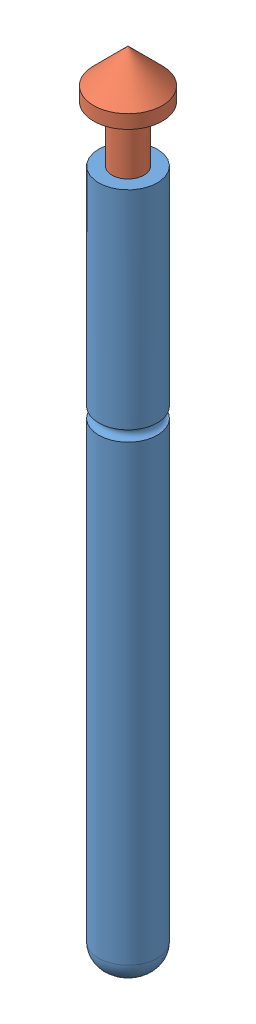
SolidWorks assembly P75-E2, configuration Work. Lengths in mm.
Overall size (1.34 14.95 1.34).
2 component instances, 2 part files, 2 mates.
Components (placement in the parent):
- Barrel^P75-E2-1: Barrel^P75-E2 [Default] at origin (virtual)
- Plunger^P75-E2-1: Plunger^P75-E2 [Default] at (0 11.05 0) x (0.999365 0 -0.035623) z (0.035623 0 0.999365) (virtual)
Mates (geometry in assembly coordinates):
- Concentric1: concentric anti-aligned: cylinder of Barrel^P75-E2-1 through (0 13 0) axis (0 -1 0) radius 0.55; cylinder of Plunger^P75-E2-1 through (0 14.95 0) axis (0 1 0) radius 0.3
- LimitDistance1: limit distance = 14.95 mm: plane of Barrel^P75-E2-1 through (0 0 0) normal (0 -1 0); point of Plunger^P75-E2-1
